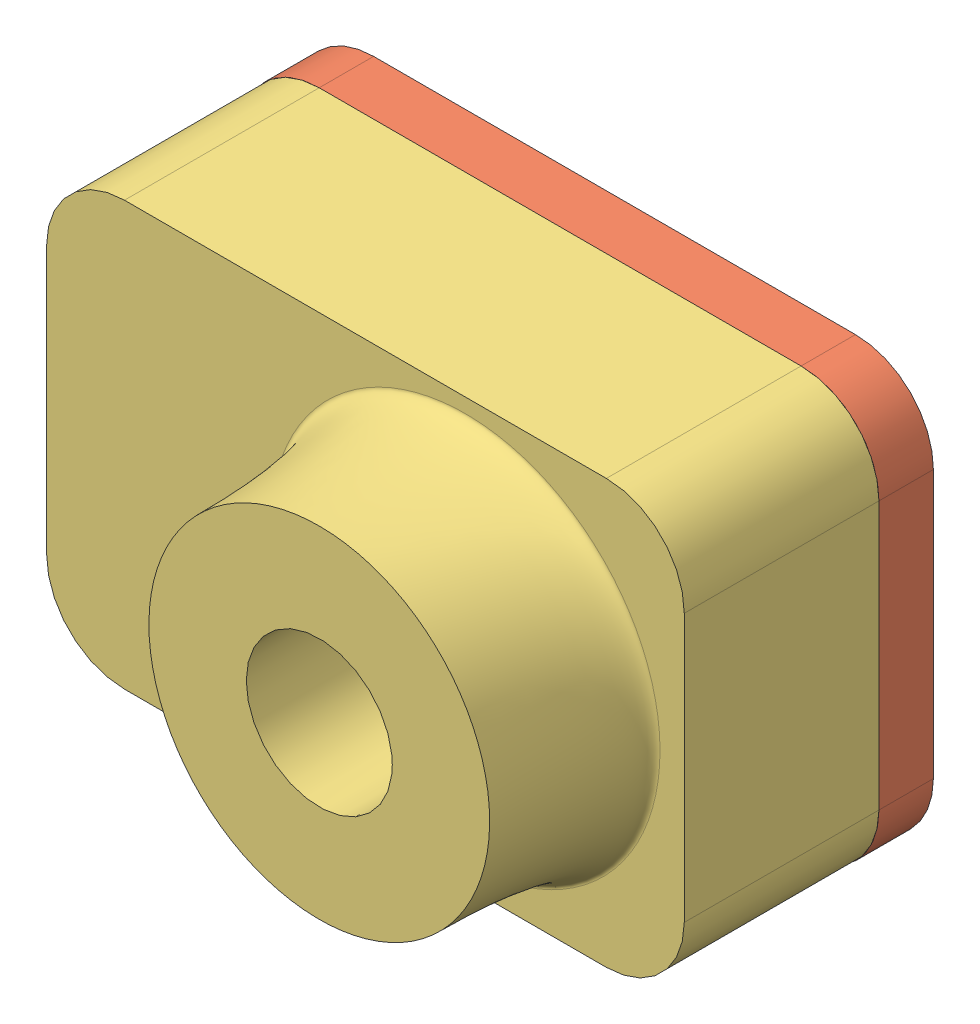
SolidWorks assembly Top Level, configuration Default. Lengths in mm.
Overall size (417.5 43.5 40.92).
3 component instances, 3 part files, 3 mates.
Components (placement in the parent):
- PCB-1: PCB [Default] at origin size (61.74 37.52 15.91)
- Part1-1: Part1 [Default] at origin size (417.5 43.5 9.05)
- Part2-1: Part2 [Default] at origin size (65.5 43.5 35.01)
Mates (geometry in assembly coordinates):
- Coincident7: coordinate: point of Part1-1; point of PCB-1
- Coincident8: coordinate: unknown of Part1-1
- Coincident10: coincident: point of assembly; point of Part2-1; point of assembly
